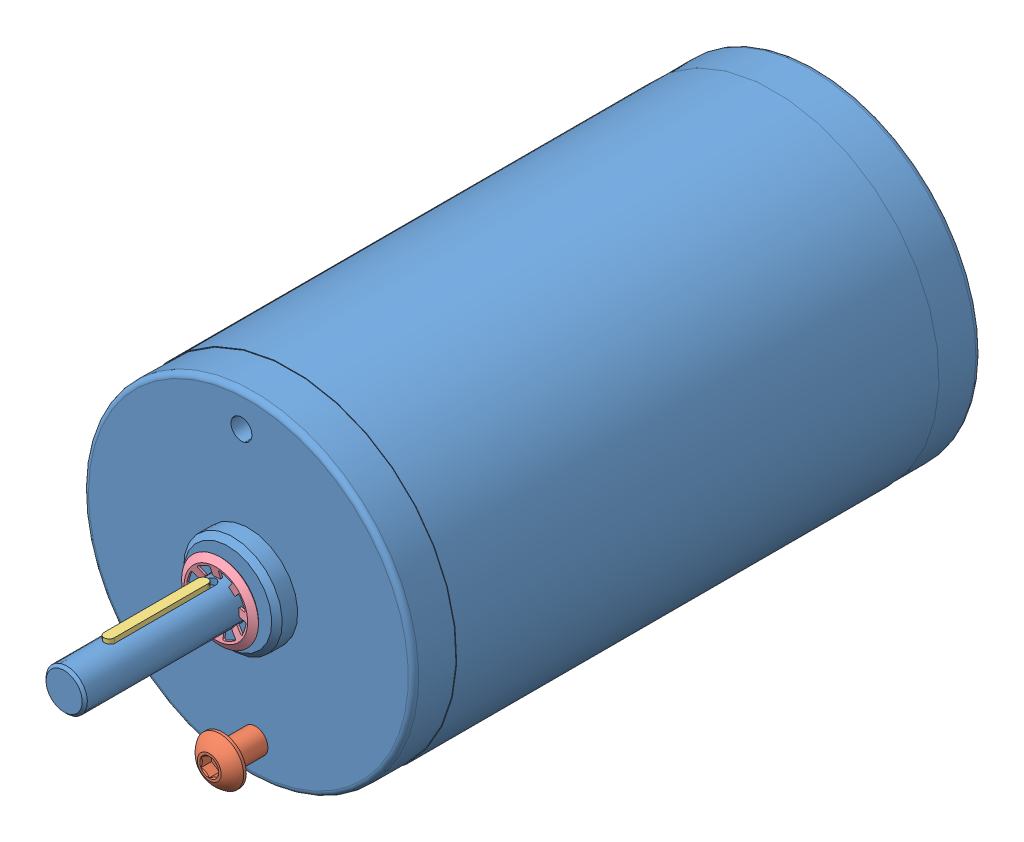
SolidWorks assembly CIM Motor for WCP SS, configuration Default. Lengths in mm.
Overall size (67.32 67.32 150.2).
4 component instances, 4 part files, 4 mates.
Components (placement in the parent):
- 217-2000-1: 217-2000 [Default] at (-51.94 43.6392 -54.598) x (0 0 -1) z (0.998588 0.053124 0) size (150.2 64.01 64.01)
- 217-3421-009 Rev1-4: 217-3421-009 Rev1 [Default] at (-50.5906 18.275 -48.248) x (0 0 -1) z (-0.521716 -0.853119 0) size (15.78 9.26 9.25)
- 217-2761-001 rev1-2: 217-2761-001 rev1 [Default] at (-52.1418 47.4338 -36.998) x (0.998588 0.053124 0) z (0 0 1) size (2 2 20)
- 217-2614-002_98430A132-3: 217-2614-002_98430A132 [Default] at (-51.94 43.6392 -48.312) x (0 0 -1) z (0.996945 0.078111 0) size (1.2 14.83 14.83)
Mates (geometry in assembly coordinates):
- Concentric43: concentric aligned: cylinder of 217-2000-1 through (-52.1457 47.5067 -27.998) axis (0.053124 -0.998588 0) radius 1; cylinder of 217-2761-001 rev1-2 through (-52.195 48.4324 -27.998) axis (0.053124 -0.998588 0) radius 1
- Coincident55: coincident anti-aligned: plane of 217-2000-1 through (-53.0873 46.3821 -26.998) normal (-0.053124 0.998588 0); plane of 217-2761-001 rev1-2 through (-53.0873 46.3821 -26.998) normal (0.053124 -0.998588 0)
- Concentric47: concentric aligned: cylinder of 217-2000-1 through (-50.5906 18.275 -54.598) axis (0 0 1) radius 2.0193; cylinder of 217-3421-009 Rev1-4 through (-50.5906 18.275 -60.948) axis (0 0 1) radius 2.413
- Distance7: distance = 6.35 mm anti-aligned: plane of 217-2000-1 through (-52.446 53.1507 -54.598) normal (0 0 1); plane of 217-3421-009 Rev1-4 through (-46.6793 15.8831 -48.248) normal (0 0 -1)
